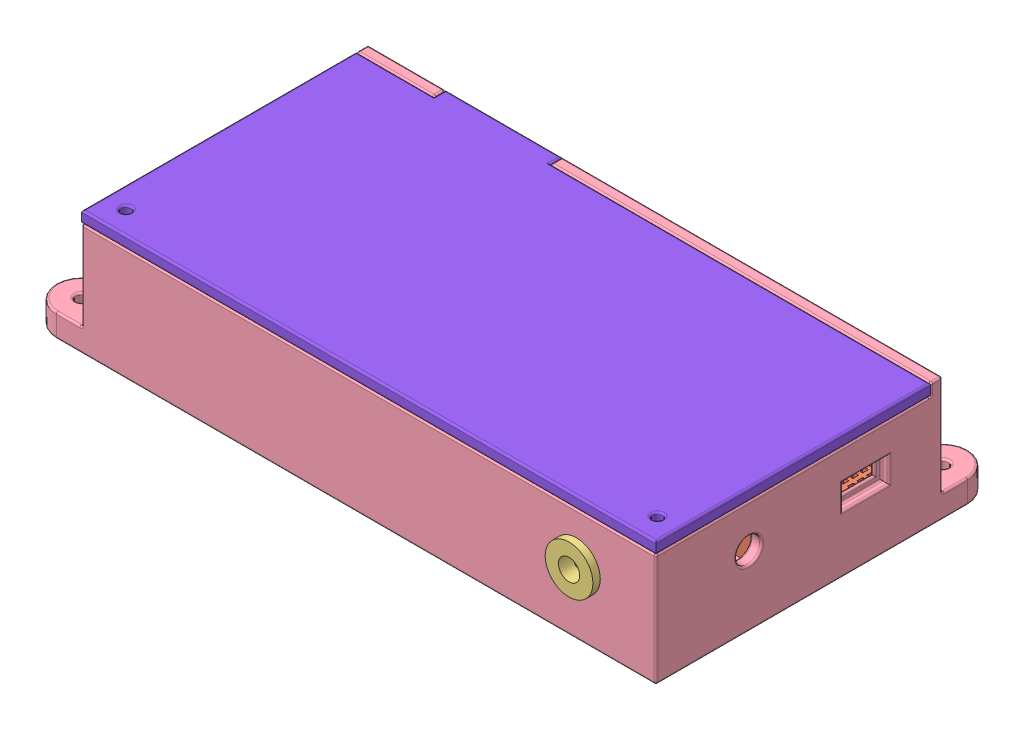
SolidWorks assembly Electrical Box Reference Assembly, configuration Default. Lengths in mm.
Overall size (161 32 88.7).
10 component instances, 8 part files, 30 mates.
Components (placement in the parent):
- DC DC Converter 5V-1: DC DC Converter 5V [Default] at origin size (76.1 19 31.3)
- Breadboard - Mini Modular (No adhesive)-1: Breadboard - Mini Modular (No adhesive) [Default] at (0 0 -33.65) x (0 0 -1) z (1 0 0) size (36.4 8.2 48.4)
- Breadboard - Mini Modular (No adhesive)-2: Breadboard - Mini Modular (No adhesive) [Default] at (47 0 -33.65) x (0 0 -1) z (1 0 0) size (36.4 8.2 48.4)
- Breadboard - Mini Modular (No adhesive)-3: Breadboard - Mini Modular (No adhesive) [Default] at (-47 0 -33.65) x (0 0 -1) z (1 0 0) size (36.4 8.2 48.4)
- 21 55 Barrel Jack-1: 21 55 Barrel Jack [Default] at (53.5 12.5 19.15) x (-1 0 0) z (0 0 1) size (12.3 12.3 25.9)
- Electrical Box-1: Electrical Box [Default] x (-1 0 0) z (0 -1 0) size (161 86.8 32)
- Barrel Jack Nut-1: Barrel Jack Nut [Default] at (53.5 12.5 12.95) x (0.866025 0.5 0) z (0 0 1) size (15.93 13.8 2.2)
- Barrel Jack Washer-1: Barrel Jack Washer [Default] at (53.5 12.5 15.15) size (14 14 1)
- Cable Lock-2: Cable Lock [Default] at (-71 0 0) x (0 -1 0) z (1 0 0) size (5.75 28.3 8.5)
- Electrical Box Lid-1: Electrical Box Lid [Default] at (0 25 0) x (1 0 0) z (0 1 0) size (148 73.8 10)
Mates (geometry in assembly coordinates):
- Coincident1: coordinate: point of DC DC Converter 5V-1
- Coincident2: coincident aligned: plane of DC DC Converter 5V-1 through (0 0 0) normal (0 -1 0); plane of Breadboard - Mini Modular (No adhesive)-1 through (0 0 -33.65) normal (0 -1 0)
- Coincident3: coincident aligned: plane of DC DC Converter 5V-1 through (0 0 0) normal (0 -1 0); plane of Breadboard - Mini Modular (No adhesive)-2 through (47 0 -33.65) normal (0 -1 0)
- Coincident4: coincident aligned: plane of DC DC Converter 5V-1 through (0 0 0) normal (0 -1 0); plane of Breadboard - Mini Modular (No adhesive)-3 through (-47 0 -33.65) normal (0 -1 0)
- Coincident5: coincident aligned: plane of Breadboard - Mini Modular (No adhesive)-1 through (-23.5 5.2 -16.15) normal (0 0 1); plane of Breadboard - Mini Modular (No adhesive)-3 through (-70.5 5.2 -16.15) normal (0 0 1)
- Coincident6: coincident anti-aligned: plane of Breadboard - Mini Modular (No adhesive)-1 through (-23.5 5.2 -33.65) normal (-1 0 0); plane of Breadboard - Mini Modular (No adhesive)-3 through (-23.5 5.2 -33.65) normal (1 0 0)
- Coincident7: coincident anti-aligned: plane of Breadboard - Mini Modular (No adhesive)-1 through (23.5 5.2 -33.65) normal (1 0 0); plane of Breadboard - Mini Modular (No adhesive)-2 through (23.5 5.2 -33.65) normal (-1 0 0)
- Coincident8: coincident aligned: plane of Breadboard - Mini Modular (No adhesive)-1 through (-23.5 5.2 -16.15) normal (0 0 1); plane of Breadboard - Mini Modular (No adhesive)-2 through (23.5 5.2 -16.15) normal (0 0 1)
- Distance1: distance = 0.5 mm anti-aligned: plane of DC DC Converter 5V-1 through (-38.05 5 -15.65) normal (0 0 -1); plane of Breadboard - Mini Modular (No adhesive)-1 through (-23.5 5.2 -16.15) normal (0 0 1)
- Coincident11: coincident aligned: plane of Breadboard - Mini Modular (No adhesive)-1 through (0 0 -33.65) normal (1 0 0)
- InPlace1: in place: plane of DC DC Converter 5V-1 through (0 0 0) normal (0 -1 0); plane of Electrical Box-1 through (0 0 0) normal (0 -1 0); moOrthogonalPlaneRef_w of DC DC Converter 5V-1 through (0 0 0) normal (0 -1 0); plane of Electrical Box-1 through (0 0 0) normal (0 0 -1); plane of DC DC Converter 5V-1 through (0 0 0) normal (0 -1 0); plane of Electrical Box-1 through (0 0 0) normal (-1 0 0); plane of DC DC Converter 5V-1 through (0 0 0) normal (0 -1 0); unknown of Electrical Box-1
- Coincident12: coincident aligned: plane of DC DC Converter 5V-1; plane of Electrical Box-1
- Coincident13: coincident aligned: moOrthogonalPlaneRef_w of DC DC Converter 5V-1 through (0 0 0) normal (0 0 -1); plane of Electrical Box-1 through (0 0 0) normal (0 0 -1)
- Coincident14: coincident anti-aligned: moOrthogonalPlaneRef_w of DC DC Converter 5V-1 through (0 0 0) normal (1 0 0); plane of Electrical Box-1 through (0 0 0) normal (-1 0 0)
- Concentric1: concentric anti-aligned: cylinder of 21 55 Barrel Jack-1 through (53.5 12.5 4.75) axis (0 0 1) radius 5.35; cylinder of Electrical Box-1 through (53.5 12.5 19.15) axis (0 0 -1) radius 5.5
- Coincident12: coincident anti-aligned: plane of 21 55 Barrel Jack-1 through (53.5 12.5 19.15) normal (0 0 -1); plane of Electrical Box-1 through (0 -1.5 19.15) normal (0 0 1)
- Parallel1: parallel aligned: plane of 21 55 Barrel Jack-1 through (52 7.5646 -4.85) normal (0 1 0); plane of Electrical Box-1 through (0 0 0) normal (0 1 0)
- Concentric2: concentric anti-aligned: cylinder of 21 55 Barrel Jack-1 through (53.5 12.5 4.75) axis (0 0 1) radius 5.35; cylinder of Barrel Jack Washer-1 through (53.5 12.5 16.15) axis (0 0 -1) radius 5.6
- Coincident14: coincident anti-aligned: plane of Electrical Box-1 through (0 25 16.15) normal (0 0 -1); plane of Barrel Jack Washer-1 through (53.5 12.5 16.15) normal (0 0 1)
- Concentric3: concentric anti-aligned: cylinder of 21 55 Barrel Jack-1 through (53.5 12.5 4.75) axis (0 0 1) radius 5.35; cylinder of Barrel Jack Nut-1 through (53.5 12.5 15.15) axis (0 0 -1) radius 4.9
- Coincident15: coincident anti-aligned: plane of Barrel Jack Nut-1 through (53.5 12.5 15.15) normal (0 0 1); plane of Barrel Jack Washer-1 through (53.5 12.5 15.15) normal (0 0 -1)
- Parallel3: parallel aligned: plane of Electrical Box-1 through (71 25 0) normal (-1 0 0); plane of Barrel Jack Nut-1 through (46.6 16.4837 15.15) normal (-1 0 0)
- InPlace2: in place: plane of Electrical Box-1 through (-70.5 20 0) normal (1 0 0); plane of ? through (-70.5 0 0) normal (1 0 0); plane of Electrical Box-1 through (-70.5 20 0) normal (1 0 0); plane of ? through (-70.5 0 0) normal (0 1 0); plane of Electrical Box-1 through (-70.5 20 0) normal (1 0 0); plane of ? through (-70.5 0 0) normal (0 0 -1); plane of Electrical Box-1 through (-71 25 0) normal (1 0 0); unknown of Cable Lock-2
- Coincident18: coincident aligned: plane of Electrical Box-1; plane of Cable Lock-2
- Coincident19: coincident aligned: moOrthogonalPlaneRef_w of Electrical Box-1 through (-71 0 0) normal (0 0 -1); plane of Cable Lock-2 through (-71 0 0) normal (0 0 -1)
- Coincident20: coincident anti-aligned: moOrthogonalPlaneRef_w of Electrical Box-1 through (-71 0 0) normal (0 1 0); plane of Cable Lock-2 through (-71 0 0) normal (0 -1 0)
- InPlace3: in place: plane of Electrical Box-1 through (0 20 0) normal (0 1 0); plane of ? through (0 20 0) normal (0 1 0); plane of Electrical Box-1 through (0 20 0) normal (0 1 0); plane of ? through (0 20 0) normal (0 0 -1); plane of Electrical Box-1 through (0 20 0) normal (0 1 0); plane of ? through (0 20 0) normal (1 0 0); plane of Electrical Box-1 through (0 25 0) normal (0 1 0); unknown of Electrical Box Lid-1
- Coincident16: coincident aligned: plane of Electrical Box-1; plane of Electrical Box Lid-1
- Coincident17: coincident aligned: moOrthogonalPlaneRef_w of Electrical Box-1 through (0 25 0) normal (0 0 -1); plane of Electrical Box Lid-1 through (0 25 0) normal (0 0 -1)
- Coincident18: coincident anti-aligned: moOrthogonalPlaneRef_w of Electrical Box-1 through (0 25 0) normal (-1 0 0); plane of Electrical Box Lid-1 through (0 25 0) normal (1 0 0)
